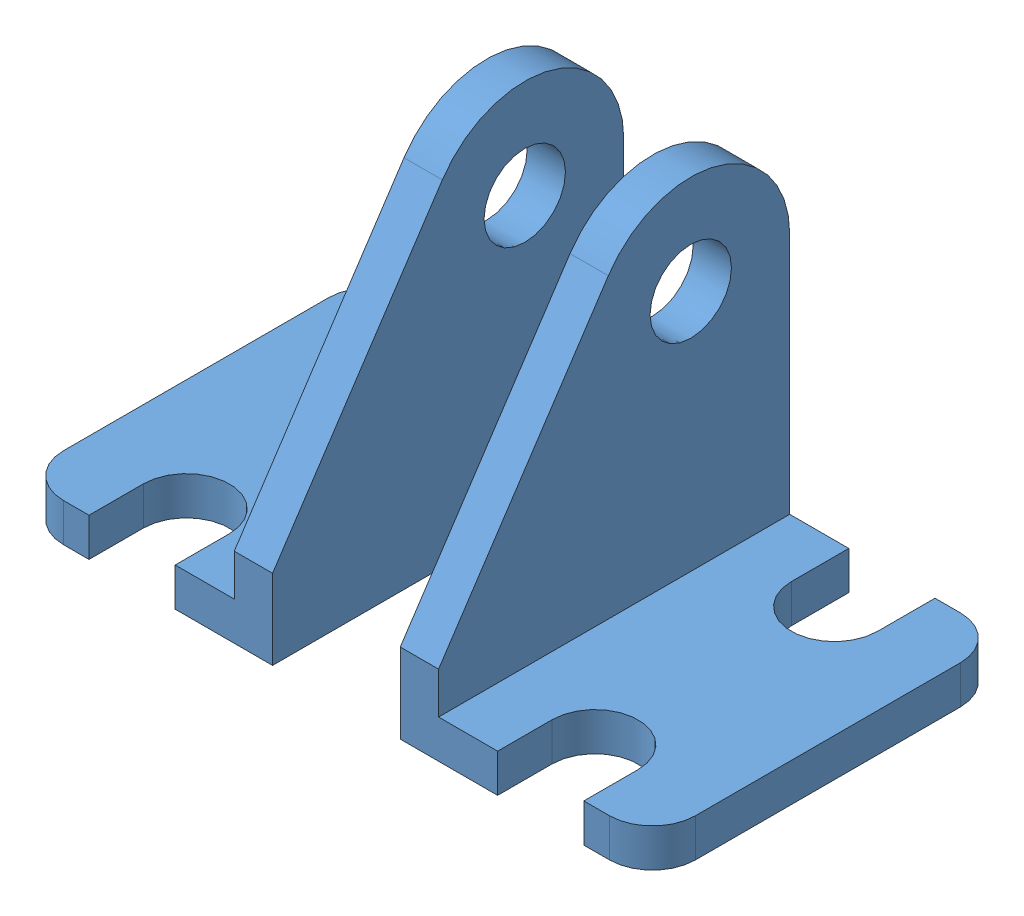
SolidWorks assembly Frame Side Brackets (NCM-PC075), configuration NCM-PC075. Lengths in mm.
Overall size (50.29 30.23 27.94).
2 component instances, 1 part files, 6 mates.
Components (placement in the parent):
- NCM-PC075_NCMP-C-Bracket-1: NCM-PC075_NCMP-C-Bracket [075F] at (5.08 0 0) size (20.07 30.23 27.94)
- NCM-PC075_NCMP-C-Bracket-2: NCM-PC075_NCMP-C-Bracket [075R] at (-5.08 0 0) x (-1 0 0) z (0 0 -1) size (20.07 30.23 27.94)
Mates (geometry in assembly coordinates):
- Coincident1: coincident aligned: plane of NCM-PC075_NCMP-C-Bracket-1 through (5.08 0 0) normal (0 1 0); plane of assembly through (0 0 0) normal (0 1 0)
- Coincident2: coincident aligned: plane of NCM-PC075_NCMP-C-Bracket-1 through (5.08 0 0) normal (0 1 0); plane of NCM-PC075_NCMP-C-Bracket-2
- Coincident3: coincident aligned: plane of NCM-PC075_NCMP-C-Bracket-1 through (5.08 0 0) normal (0 0 1); plane of assembly through (0 0 0) normal (0 0 1)
- Coincident4: coincident anti-aligned: plane of NCM-PC075_NCMP-C-Bracket-1 through (5.08 0 0) normal (0 0 1); plane of NCM-PC075_NCMP-C-Bracket-2 through (-5.08 0 0) normal (0 0 -1)
- Symmetric1: symmetric aligned: plane of NCM-PC075_NCMP-C-Bracket-1 through (5.08 0 0) normal (1 0 0); plane of NCM-PC075_NCMP-C-Bracket-2 through (-5.08 0 0) normal (-1 0 0); plane of assembly through (0 0 0) normal (1 0 0)
- Distance1: distance = 10.16 mm anti-aligned: plane of NCM-PC075_NCMP-C-Bracket-1 through (5.08 3.048 13.97) normal (-1 0 0); plane of NCM-PC075_NCMP-C-Bracket-2 through (-5.08 3.048 -13.97) normal (1 0 0)
